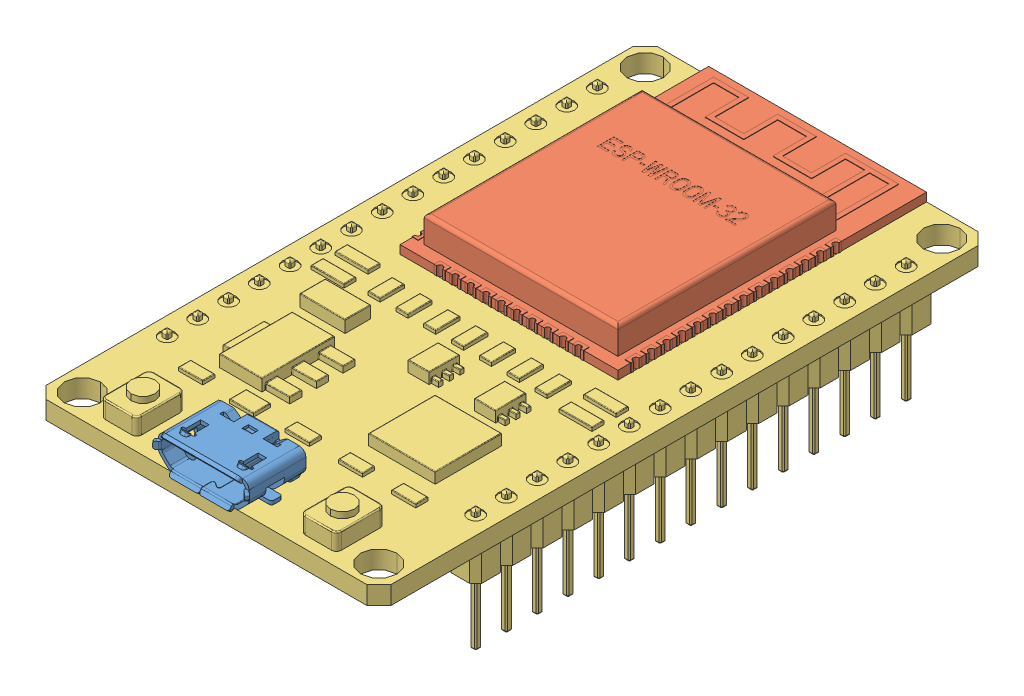
SolidWorks assembly ESP-WROOM32, configuration Default. Lengths in mm.
Overall size (28.5 12.4 50.93).
4 component instances, 3 part files, 0 mates.
Components (placement in the parent):
- ESP-WROOM32.STEP-1: ESP-WROOM32.STEP [Default] at origin size (28.5 12.4 50.93)
  - micro_usb_47346-0001.STEP-1: micro_usb_47346-0001.STEP [Default] at (-1.7662 -0.0714 7.915) size (7.98 2.94 5.43)
  - ESP-WROOM-32.STEP-1: ESP-WROOM-32.STEP [Default] at (-1.5465 -1.4314 -27.485) x (-1 0 0) z (0 1 0) size (18.07 25.54 3.04)
  - 6.ESP-32_Predeterminado.STEP-1: 6.ESP-32_Predeterminado.STEP [Default] at (-1.5465 -2.7964 -14.985) size (28.5 11.4 50.5)
